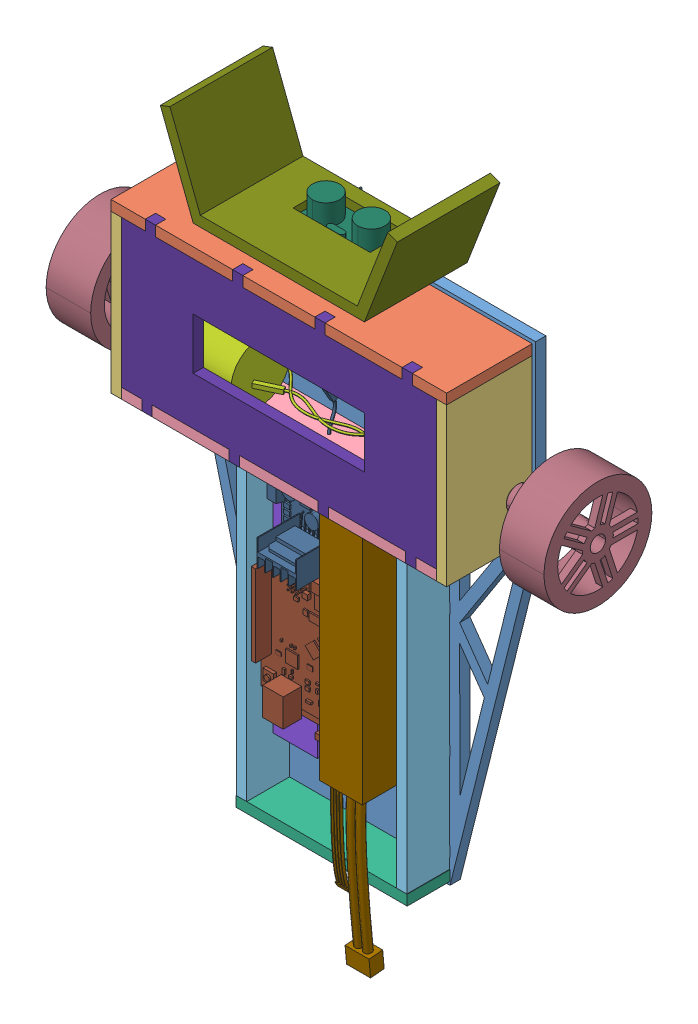
SolidWorks assembly design_functional, configuration 기본. Lengths in mm.
Overall size (290.8 392.49 151.94).
22 component instances, 17 part files, 57 mates.
Components (placement in the parent):
- bottom-1: bottom [기본] at (17.9171 -162.0104 297) size (200 300 6)
- frontWall-1: frontWall [기본] at (17.9171 129.9896 303) size (196 6 151.94)
- sideWall x2-1: sideWall x2 [기본] at (109.9171 83.9896 303) x (0 -1 0) z (0 0 1) size (92 6 56)
- sideWall x2-2: sideWall x2 [기본] at (-80.0829 83.9896 303) x (0 -1 0) z (0 0 1) size (92 6 56)
- midWall-1: midWall [기본] at (17.9171 43.9896 303) x (1 0 0) z (0 -1 0) size (184 56 6)
- midWall_2 x2-1: midWall_2 x2 [기본] at (61.6659 -58.0104 303) x (0 -1 0) z (0 0 1) size (192 6 31)
- midWall_2 x2-2: midWall_2 x2 [기본] at (-25.8316 -58.0104 303) x (0 1 0) z (0 0 1) size (192 6 31)
- backWall-1: backWall [기본] at (17.9171 -160.0104 303) size (100 6 31)
- motor.step-1: motor.step [기본] at (-22.6829 62.5396 323.0909) x (0 -0.999178 -0.040541) z (0 0.040541 -0.999178) size (37.1 151.83 37.1)
- motor.step-2: motor.step [기본] at (58.5171 62.5396 323.0909) x (0 0.999178 0.040541) z (0 0.040541 -0.999178) size (37.1 151.83 37.1)
- breadboard.step-1: breadboard.step [기본] at (1.1684 -44.5104 303) x (1 0 0) z (0 -1 0) size (54 9.6 165)
- lipo-battery.stp-1: lipo-battery.stp [기본] at (36.6659 211.7279 618.3149) x (0 0 1) z (1 0 0) size (45 230.34 25)
- motorcontroler.step-1: motorcontroler.step [기본] at (2.0184 -0.8795 312.6) x (1 0 0) z (0 -1 0) size (55.7 26.71 104.61)
- arduino-UNO.step-1: arduino-UNO.step [기본] at (2.5393 -66.9971 312.6) x (1 0 0) z (0 -1 0) size (57.5 18.3 80.7)
- front-wheel.stp-1: front-wheel.stp [기본] at (453.7222 -382.8089 285) size (16 22 15.01)
- wheel-basic.step-1: wheel-basic.step [기본] at (-127.4829 62.9896 312) x (0 -1 0) z (0 0 1) size (63 46.5 63)
- wheel-basic.step-2: wheel-basic.step [기본] at (163.3171 62.9896 312) x (0 1 0) z (0 0 1) size (63 46.5 63)
- infrared-sensor.step-1: infrared-sensor.step [기본] at (-7.1329 128.4446 292.35) x (-1 0 0) z (0 -1 0) size (14.1 16.75 36)
- ultrasonic-sensor.step-1: ultrasonic-sensor.step [기본] at (17.7671 147.9896 312.0191) x (-1 0 0) z (0 0 -1) size (45.3 18.15 26.45)
- infrared-sensor.step-2: infrared-sensor.step [기본] at (42.9671 128.4446 292.35) x (-1 0 0) z (0 -1 0) size (14.1 16.75 36)
- Grabber-1: Grabber [기본] at (17.9171 147.9896 293) size (138.41 70.15 60)
- topCover-1: topCover [기본] at (17.9171 43.9896 347) size (184 98 6)
Mates (geometry in assembly coordinates):
- Coincident1: coincident anti-aligned: plane of bottom-1 through (17.9171 -162.0104 303) normal (0 0 1); plane of frontWall-1 through (17.9171 129.9896 303) normal (0 0 -1)
- Coincident2: coincident anti-aligned: plane of bottom-1 through (109.9171 135.9896 303) normal (-1 0 0); plane of frontWall-1 through (109.9171 129.9896 297) normal (1 0 0)
- Coincident3: coincident anti-aligned: plane of bottom-1 through (58.9171 129.9896 303) normal (0 1 0); plane of frontWall-1 through (115.9171 129.9896 353) normal (0 -1 0)
- Coincident4: coincident anti-aligned: plane of bottom-1 through (17.9171 -162.0104 303) normal (0 0 1); plane of sideWall x2-1 through (109.9171 83.9896 303) normal (0 0 -1)
- Coincident5: coincident anti-aligned: plane of bottom-1 through (109.9171 47.9896 303) normal (1 0 0); plane of sideWall x2-1 through (109.9171 129.9896 353) normal (-1 0 0)
- Coincident6: coincident anti-aligned: plane of bottom-1 through (109.9171 119.9896 303) normal (0 -1 0); plane of sideWall x2-1 through (109.9171 119.9896 297) normal (0 1 0)
- Coincident7: coincident anti-aligned: plane of bottom-1 through (17.9171 -162.0104 303) normal (0 0 1); plane of sideWall x2-2 through (-80.0829 83.9896 303) normal (0 0 -1)
- Coincident8: coincident anti-aligned: plane of bottom-1 through (-74.0829 113.9896 303) normal (-1 0 0); plane of sideWall x2-2 through (-74.0829 129.9896 353) normal (1 0 0)
- Coincident9: coincident anti-aligned: plane of bottom-1 through (-74.0829 119.9896 303) normal (0 -1 0); plane of sideWall x2-2 through (-80.0829 119.9896 297) normal (0 1 0)
- Coincident10: coincident anti-aligned: plane of bottom-1 through (17.9171 -162.0104 303) normal (0 0 1); plane of midWall-1 through (109.9171 37.9896 303) normal (0 0 -1)
- Coincident11: coincident anti-aligned: plane of bottom-1 through (-68.0829 43.9896 303) normal (1 0 0); plane of midWall-1 through (-68.0829 37.9896 297) normal (-1 0 0)
- Coincident12: coincident anti-aligned: plane of bottom-1 through (-62.0829 43.9896 303) normal (0 -1 0); plane of midWall-1 through (17.9171 43.9896 303) normal (0 1 0)
- Coincident13: coincident anti-aligned: plane of bottom-1 through (17.9171 -162.0104 303) normal (0 0 1); plane of backWall-1 through (17.9171 -160.0104 303) normal (0 0 -1)
- Coincident14: coincident anti-aligned: plane of bottom-1 through (29.9171 -154.0104 303) normal (0 -1 0); plane of backWall-1 through (-32.0829 -154.0104 328) normal (0 1 0)
- Coincident15: coincident anti-aligned: plane of bottom-1 through (-20.0829 -160.0104 303) normal (-1 0 0); plane of backWall-1 through (-20.0829 -160.0104 297) normal (1 0 0)
- Coincident16: coincident anti-aligned: plane of bottom-1 through (17.9171 -162.0104 303) normal (0 0 1); plane of midWall_2 x2-1 through (61.6659 -58.0104 303) normal (0 0 -1)
- Coincident17: coincident anti-aligned: plane of bottom-1 through (61.6659 31.9896 303) normal (1 0 0); plane of midWall_2 x2-1 through (61.6659 -154.0104 328) normal (-1 0 0)
- Coincident18: coincident anti-aligned: plane of bottom-1 through (61.9171 -148.0104 303) normal (0 1 0); plane of midWall_2 x2-1 through (67.6659 -148.0104 303) normal (0 -1 0)
- Coincident19: coincident anti-aligned: plane of bottom-1 through (-25.8316 31.9896 303) normal (-1 0 0); plane of midWall_2 x2-2 through (-25.8316 37.9896 328) normal (1 0 0)
- Coincident20: coincident anti-aligned: plane of bottom-1 through (-26.0829 -148.0104 303) normal (0 1 0); plane of midWall_2 x2-2 through (-31.8316 -148.0104 303) normal (0 -1 0)
- Coincident21: coincident anti-aligned: plane of bottom-1 through (17.9171 -162.0104 303) normal (0 0 1); plane of midWall_2 x2-2 through (-25.8316 -58.0104 303) normal (0 0 -1)
- Coincident22: coincident: plane of sideWall x2-2 through (-74.0829 129.9896 353) normal (1 0 0); plane of motor.step-1 through (-74.0829 62.5396 323.0909) normal (-1 0 0)
- Concentric1: concentric: cylinder of sideWall x2-2 through (-74.0829 62.9896 312) axis (-1 0 0) radius 6; cylinder of motor.step-1 through (-80.9829 62.9896 312) axis (1 0 0) radius 6
- Tangent1: tangent: plane of midWall-1 through (17.9171 43.9896 303) normal (0 1 0); cylinder of motor.step-1 through (-74.0829 62.5396 323.0909) axis (1 0 0) radius 18.55
- Coincident23: coincident: plane of sideWall x2-1 through (109.9171 129.9896 353) normal (-1 0 0); plane of motor.step-2 through (109.9171 62.5396 323.0909) normal (1 0 0)
- Concentric2: concentric: cylinder of sideWall x2-1 through (115.9171 62.9896 312) axis (-1 0 0) radius 6; cylinder of motor.step-2 through (116.8171 62.9896 312) axis (-1 0 0) radius 6
- Tangent2: tangent: plane of midWall-1 through (17.9171 43.9896 303) normal (0 1 0); cylinder of motor.step-2 through (109.9171 62.5396 323.0909) axis (-1 0 0) radius 18.55
- Coincident24: coincident: plane of midWall_2 x2-2 through (-25.8316 37.9896 328) normal (1 0 0); plane of breadboard.step-1 through (-25.8316 37.9896 312.6) normal (-1 0 0)
- Coincident25: coincident: plane of bottom-1 through (17.9171 -162.0104 303) normal (0 0 1); plane of breadboard.step-1 through (1.1684 -44.5104 303) normal (0 0 -1)
- Coincident26: coincident: plane of midWall-1 through (17.9171 37.9896 303) normal (0 -1 0); plane of breadboard.step-1 through (-25.8316 37.9896 312.6) normal (0 1 0)
- Coincident27: coincident: plane of bottom-1 through (17.9171 -162.0104 303) normal (0 0 1); plane of lipo-battery.stp-1 through (36.6659 -102.0104 303) normal (0 0 -1)
- Coincident30: coincident: plane of midWall_2 x2-1 through (61.6659 -154.0104 328) normal (-1 0 0); plane of lipo-battery.stp-1 through (61.6659 37.9896 303) normal (1 0 0)
- Coincident31: coincident: plane of midWall-1 through (17.9171 37.9896 303) normal (0 -1 0); plane of lipo-battery.stp-1 through (36.6659 37.9896 303) normal (0 1 0)
- Coincident32: coincident anti-aligned: plane of bottom-1 through (17.9171 -162.0104 297) normal (0 0 -1); plane of front-wheel.stp-1 through (6.2997 -127.4584 297) normal (0 0 1)
- Coincident33: coincident: plane of motor.step-1 through (-80.9829 62.9896 312) normal (-1 0 0); plane of wheel-basic.step-1 through (-80.9829 62.9896 312) normal (1 0 0)
- Concentric3: concentric: cylinder of motor.step-1 through (-96.4829 62.9896 312) axis (1 0 0) radius 2.95; cylinder of wheel-basic.step-1 through (-80.9829 62.9896 312) axis (-1 0 0) radius 4.5
- Coincident36: coincident: plane of motor.step-2 through (116.8171 62.9896 312) normal (1 0 0); plane of wheel-basic.step-2 through (116.8171 62.9896 312) normal (-1 0 0)
- Concentric4: concentric: cylinder of motor.step-2 through (132.3171 62.9896 312) axis (-1 0 0) radius 2.95; cylinder of wheel-basic.step-2 through (116.8171 62.9896 312) axis (1 0 0) radius 4.5
- Coincident37: coincident anti-aligned: plane of frontWall-1 through (-4.5829 135.9896 336.5) normal (1 0 0); plane of Grabber-1 through (-4.5829 129.9896 336.5) normal (-1 0 0)
- Coincident38: coincident anti-aligned: plane of frontWall-1 through (-4.5829 135.9896 330.5) normal (0 0 1); plane of Grabber-1 through (-4.5829 129.9896 330.5) normal (0 0 -1)
- Coincident39: coincident aligned: plane of frontWall-1 through (115.9171 129.9896 353) normal (0 -1 0); plane of Grabber-1 through (17.9171 129.9896 293) normal (0 -1 0)
- Coincident44: coincident anti-aligned: plane of ultrasonic-sensor.step-1 through (-4.8829 149.6396 322.1691) normal (0 0 1); plane of Grabber-1 through (-4.5829 153.9896 322.1691) normal (0 0 -1)
- Coincident45: coincident anti-aligned: plane of ultrasonic-sensor.step-1 through (40.4171 149.6396 322.1691) normal (1 0 0); plane of Grabber-1 through (40.4171 153.9896 301.1691) normal (-1 0 0)
- Coincident46: coincident aligned: plane of ultrasonic-sensor.step-1 through (17.7671 147.9896 312.0191) normal (0 -1 0); plane of Grabber-1 through (67.9171 147.9896 353) normal (0 -1 0)
- Coincident47: coincident: plane of breadboard.step-1 through (1.1684 -44.5104 312.6) normal (0 0 1); plane of motorcontroler.step-1 through (2.0184 -0.8795 312.6) normal (0 0 -1)
- Coincident50: coincident anti-aligned: plane of midWall_2 x2-2 through (-25.8316 37.9896 328) normal (1 0 0); plane of motorcontroler.step-1 through (-25.8316 -0.8795 312.6) normal (-1 0 0)
- Coincident51: coincident: plane of breadboard.step-1 through (1.1684 -44.5104 312.6) normal (0 0 1); plane of arduino-UNO.step-1 through (2.5393 -66.9971 312.6) normal (0 0 -1)
- Coincident52: coincident anti-aligned: plane of midWall_2 x2-2 through (-25.8316 37.9896 328) normal (1 0 0); plane of arduino-UNO.step-1 through (-25.8316 -29.1773 319.6) normal (-1 0 0)
- Coincident53: coincident anti-aligned: plane of bottom-1 through (17.9171 -162.0104 297) normal (0 0 -1); plane of infrared-sensor.step-2 through (42.9671 128.4446 297) normal (0 0 1)
- Coincident54: coincident: plane of bottom-1 through (17.9171 -162.0104 297) normal (0 0 -1); plane of infrared-sensor.step-1 through (-7.1329 128.4446 297) normal (0 0 1)
- Coincident55: coincident anti-aligned: plane of bottom-1 through (-82.0829 137.9896 303) normal (0 1 0); plane of infrared-sensor.step-2 through (48.4171 137.9896 282.6) normal (0 -1 0)
- Coincident56: coincident: plane of bottom-1 through (-82.0829 137.9896 303) normal (0 1 0); plane of infrared-sensor.step-1 through (-1.6829 137.9896 282.6) normal (0 -1 0)
- Tangent3: tangent: circle of bottom-1; plane of infrared-sensor.step-2 through (35.9171 113.3446 290.65) normal (-1 0 0)
- Tangent4: tangent: circle of bottom-1; plane of infrared-sensor.step-1 through (-0.0829 144.5446 290.65) normal (1 0 0)
- Coincident59: coincident anti-aligned: plane of frontWall-1 through (-54.0829 129.9896 347) normal (-1 0 0); plane of topCover-1 through (-54.0829 129.9896 353) normal (1 0 0)
- Coincident60: coincident anti-aligned: plane of frontWall-1 through (-60.0829 129.9896 347) normal (0 0 1); plane of topCover-1 through (17.9171 43.9896 347) normal (0 0 -1)
- Coincident61: coincident aligned: plane of frontWall-1 through (-80.0829 135.9896 353) normal (0 1 0); plane of topCover-1 through (-54.0829 135.9896 353) normal (0 1 0)
